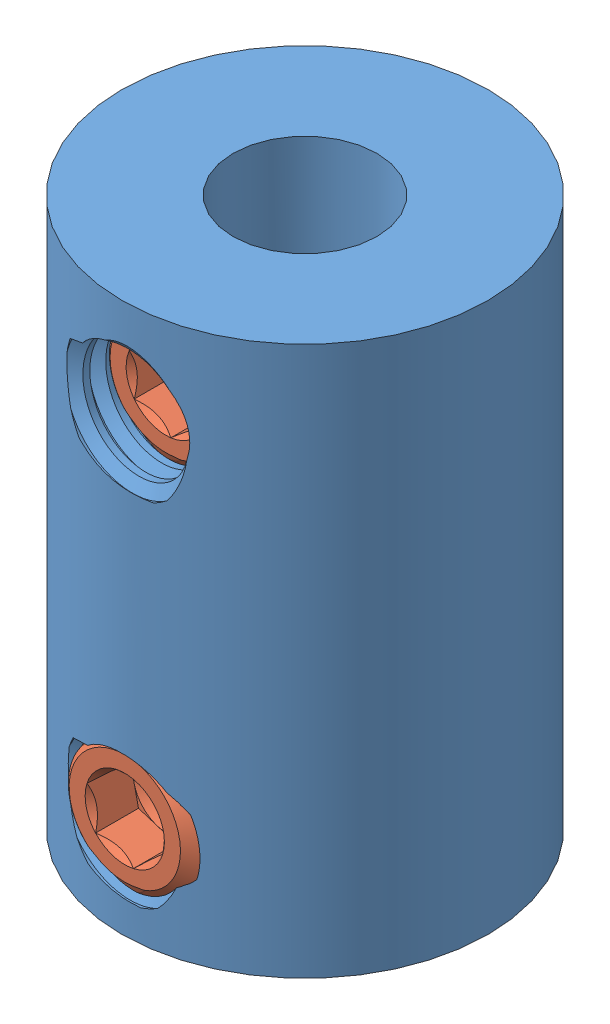
SolidWorks assembly 625228 assembly, configuration Default. Lengths in mm.
Overall size (12.69 19.05 12.78).
3 component instances, 2 part files, 0 mates.
Components (placement in the parent):
- 625228-1: 625228 [Default] at (-87.9764 2.0555 38.5038) size (12.69 19.05 12.78)
- 632134_91375A436-1: 632134_91375A436 [Default] at (-87.9764 5.4845 43.5659) x (0.97603 0.217637 0) z (0 0 1) size (4.98 4.83 3.31)
- 632134_91375A436-2: 632134_91375A436 [Default] at (-87.9764 17.6765 42.1448) x (0.991859 0.127344 0) z (0 0 1) size (4.98 4.83 3.31)
